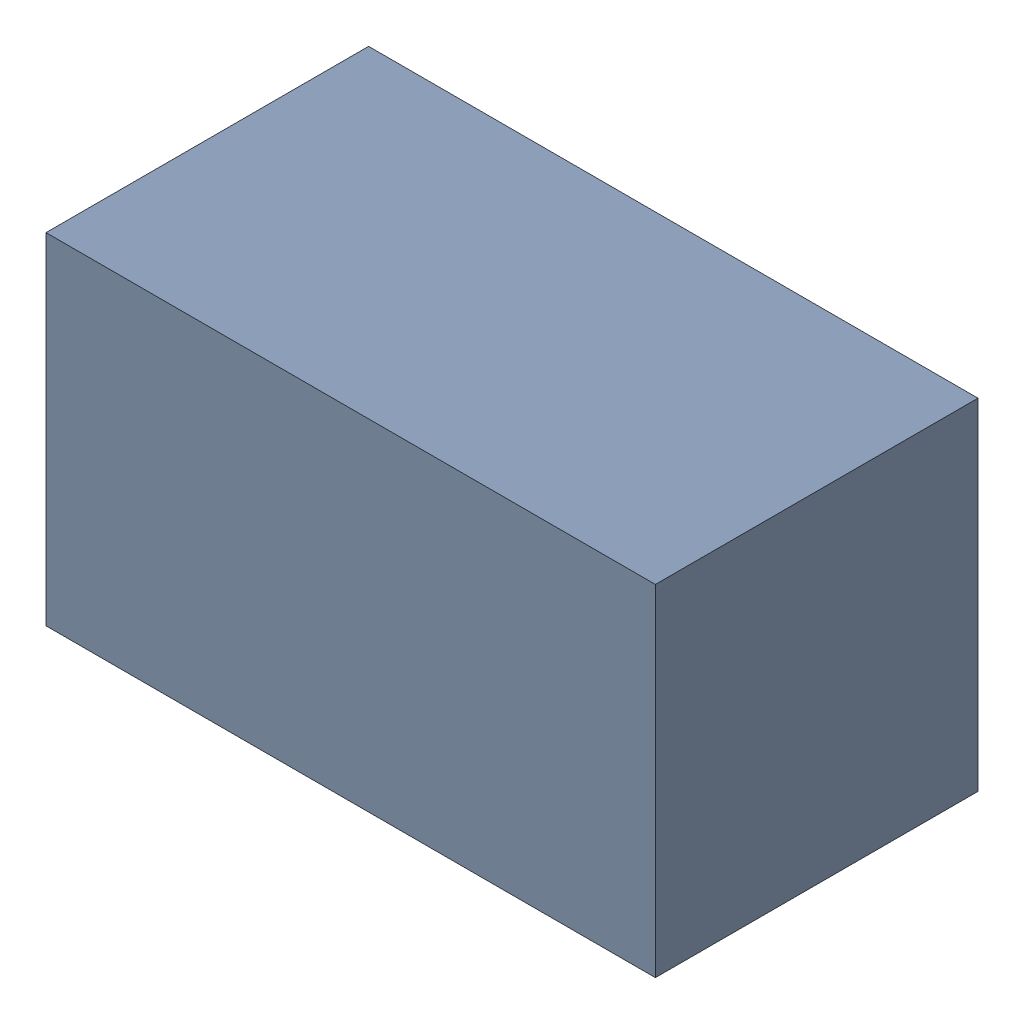
SolidWorks assembly R20, configuration Standard. Lengths in mm.
Overall size (1.7 0.95 0.9).
2 component instances, 1 part files, 0 mates.
Components (placement in the parent):
- 885541288-1: 885541288 [Standard] at (15.45 24.63 0) size (1.7 0.95 0.9)
  - Extruded_10-1: Extruded_10 [Standard] at origin size (1.7 0.95 0.9)
